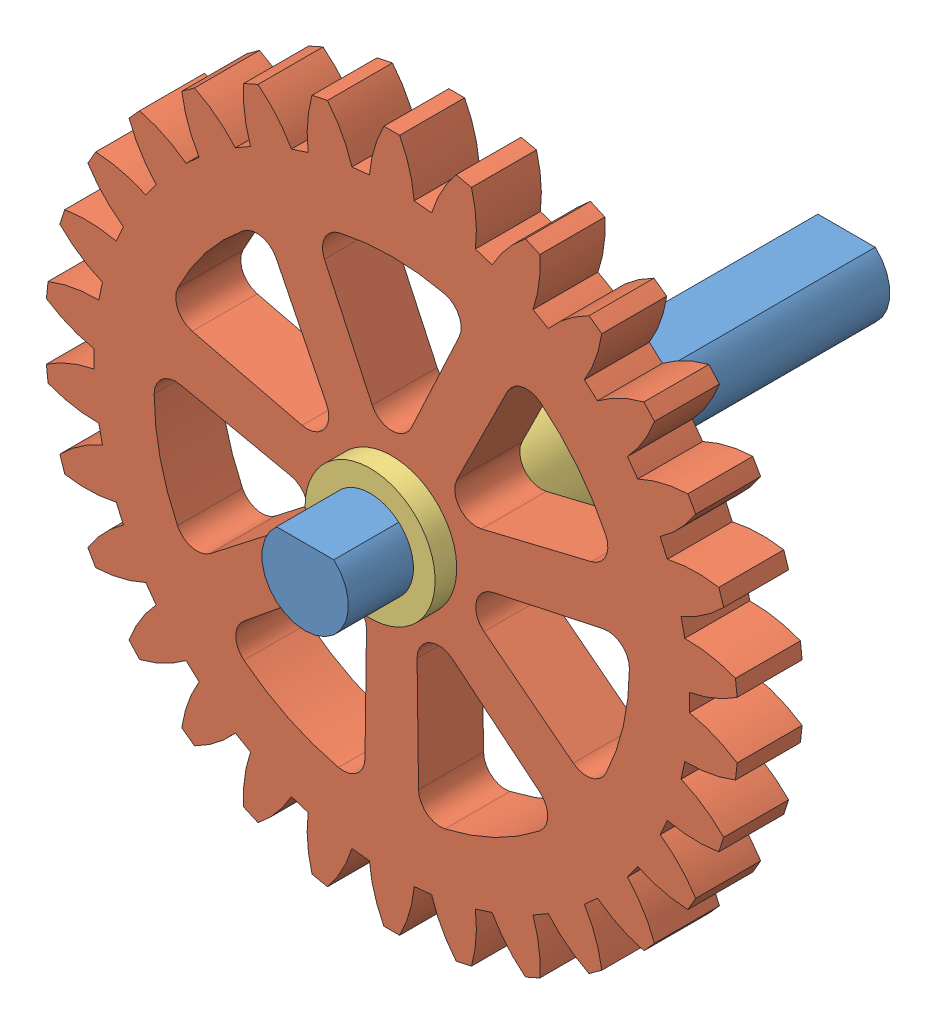
SolidWorks assembly subassem3, configuration Default. Lengths in mm.
Overall size (47.84 48 25).
4 component instances, 3 part files, 7 mates.
Components (placement in the parent):
- axle-1: axle [Long] at (4.7068 7.8968 4.6076) size (4 3.5 25)
- root_gear-1: root_gear [30T 1.5Mod] at (4.7068 7.8968 22.6076) size (47.84 48 3)
- spacer-1: spacer [4.2mm ID] at (4.7068 7.8968 25.6076) size (6 6 1)
- spacer-3: spacer [5mm Tall] at (4.7068 7.8968 17.6076) size (6 6 5)
Mates (geometry in assembly coordinates):
- Coincident1: coincident anti-aligned: plane of axle-1 through (3.3839 9.3968 29.6076) normal (0 1 0); plane of root_gear-1 through (6.0296 9.3968 32.6076) normal (0 -1 0)
- Concentric1: concentric aligned: cylinder of axle-1 through (4.7068 7.8968 29.6076) axis (0 0 -1) radius 2; cylinder of root_gear-1 through (4.7068 7.8968 32.6076) axis (0 0 -1) radius 2
- Concentric2: concentric aligned: cylinder of axle-1 through (4.7068 7.8968 29.6076) axis (0 0 -1) radius 2; cylinder of spacer-1 through (4.7068 7.8968 26.6076) axis (0 0 -1) radius 2
- Distance1: distance = 3 mm aligned: plane of spacer-1 through (4.7068 7.8968 26.6076) normal (0 0 1); plane of axle-1 through (4.7068 7.8968 29.6076) normal (0 0 1)
- Coincident3: coincident anti-aligned: plane of root_gear-1 through (4.7068 7.8968 25.6076) normal (0 0 1); plane of spacer-1 through (4.7068 7.8968 25.6076) normal (0 0 -1)
- Coincident4: coincident anti-aligned: plane of root_gear-1 through (4.7068 7.8968 22.6076) normal (0 0 -1); plane of spacer-3 through (4.7068 7.8968 22.6076) normal (0 0 1)
- Concentric3: concentric aligned: cylinder of axle-1 through (4.7068 7.8968 29.6076) axis (0 0 -1) radius 2; cylinder of spacer-3 through (4.7068 7.8968 22.6076) axis (0 0 -1) radius 2
